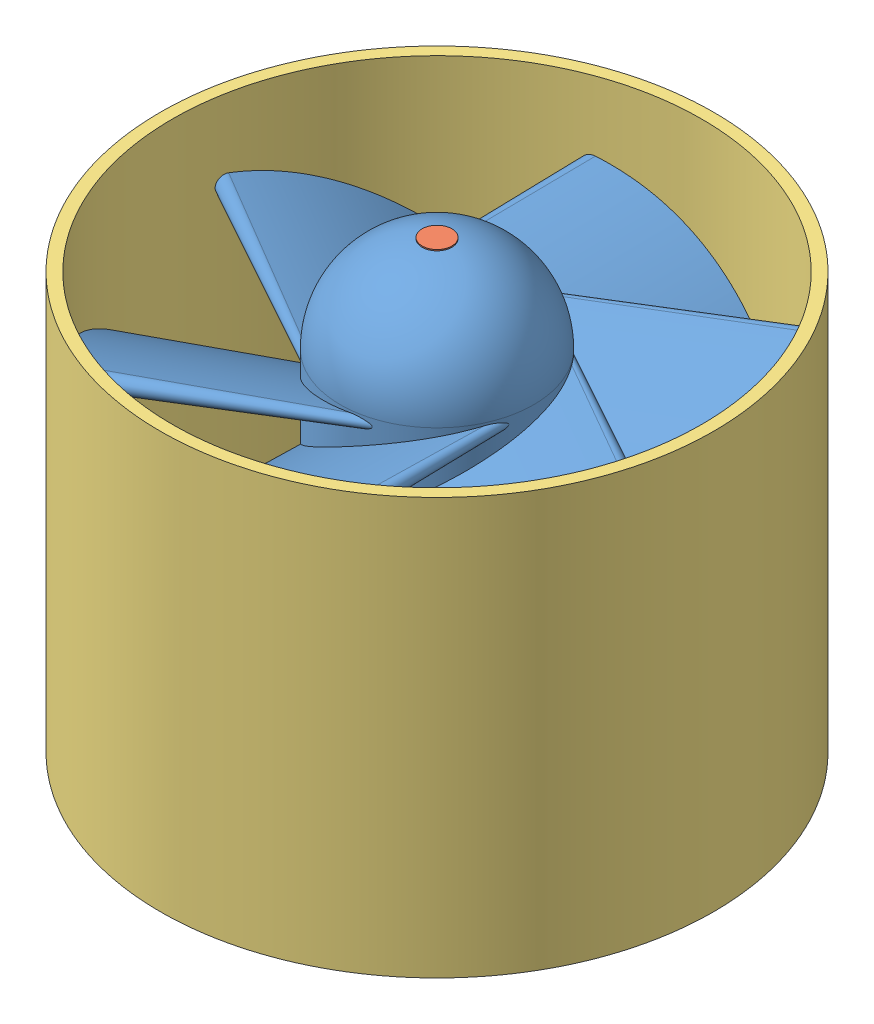
SolidWorks assembly Assemblage1, configuration Défaut. Lengths in mm.
Overall size (37.2 36 37.2).
3 component instances, 3 part files, 7 mates.
Components (placement in the parent):
- 126 Ventillateur-1: 126 Ventillateur [Défaut] at (0 3 0) size (35 13 35)
- 125 Moteur ventillateur 2-1: 125 Moteur ventillateur 2 [Défaut] at (0 -6 0) x (0 1 0) z (-0.006267 0 -0.99998) size (36 18 18)
- 127 Tube ventillateur-1: 127 Tube ventillateur [Défaut] x (0 1 0) z (0 0 -1) size (28 37.2 37.2)
Mates (geometry in assembly coordinates):
- Coaxiale17: concentric anti-aligned: cylinder of 126 Ventillateur-1 through (0 36.9949 0) axis (0 1 0) radius 6.5; cylinder of 125 Moteur ventillateur 2-1 through (0 -45.2151 0) axis (0 -1 0) radius 1
- Coaxiale18: concentric aligned: cylinder of 125 Moteur ventillateur 2-1 through (0 -45.2151 0) axis (0 -1 0) radius 9; cylinder of 127 Tube ventillateur-1 through (0 -29.9251 0) axis (0 -1 0) radius 17.8
- Coïncidente2: coincident anti-aligned: plane of 127 Tube ventillateur-1 through (0 0 0) normal (0 0 -1); plane of assembly
- Coïncidente3: coincident aligned: plane of 127 Tube ventillateur-1; plane of assembly through (0 0 0) normal (0 1 0)
- Coïncidente4: coincident aligned: plane of 127 Tube ventillateur-1; plane of assembly
- Tangent1: tangent aligned: sphere of 126 Ventillateur-1; plane of 125 Moteur ventillateur 2-1 through (0 15 0) normal (0 1 0)
- Distance1: distance = 6 mm aligned: plane of 127 Tube ventillateur-1 through (18.6 -14 0) normal (0 -1 0); plane of 125 Moteur ventillateur 2-1 through (8.9998 -20 -0.0564) normal (0 -1 0)
